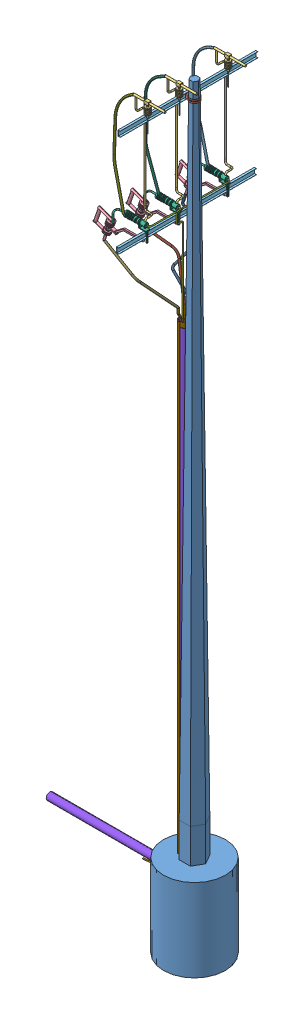
SolidWorks assembly SITEMA DE CABLEADO PARA BAJADA, configuration Predeterminado. Lengths in mm.
Overall size (2551.81 11000 2000).
25 component instances, 17 part files, 70 mates.
Components (placement in the parent):
- POSTE DE SUBESTACIÓN-1: POSTE DE SUBESTACIÓN [Predeterminado] at (-6270.6938 -6573.1724 11000) size (900 11000 900)
- FLEXX-1: FLEXX [Predeterminado] at (-6270.6938 4161.8552 11000) x (-1 0 0) z (0 0 -1) size (154.11 50 136.21)
- CONECTADOR SUPERIOR-1: CONECTADOR SUPERIOR [Predeterminado] at (-6365.6938 4181.216 10415) x (0 0 1) z (-1 0 0) size (176.67 1669.06 455)
- CORTO CIRCUITO FUSIBLE-1: CORTO CIRCUITO FUSIBLE [Predeterminado] at (-6907.9992 2496.6628 11635.8855) x (0 0 -1) z (0.943722 -0.330738 0) size (100 458.14 653.95)
- CORTO CIRCUITO FUSIBLE-2: CORTO CIRCUITO FUSIBLE [Predeterminado] at (-6892.3975 2496.6628 10460.112) x (0 0 -1) z (0.943722 -0.330738 0) size (100 458.14 653.95)
- CORTO CIRCUITO FUSIBLE-3: CORTO CIRCUITO FUSIBLE [Predeterminado] at (-6892.3975 2496.6628 11170.112) x (0 0 -1) z (0.943722 -0.330738 0) size (100 458.14 653.95)
- CRUCETA-1: CRUCETA [Predeterminado] at (-6380.6938 4146.8276 9250) size (54 80 2000)
- CRUCETA-2: CRUCETA [Predeterminado] at (-6400.6938 2666.8276 9250) size (54 80 2000)
- ELEMENTO ELEC.-1: ELEMENTO ELEC. [Predeterminado] at (-6688.5888 2810.6406 11576.0986) x (0 0 1) z (0 1 0) size (120.76 447.39 257.81)
- ELEMENTO ELEC.-2: ELEMENTO ELEC. [Predeterminado] at (-6688.5888 2810.6406 11116.0986) x (0 0 1) z (0 1 0) size (120.76 447.39 257.81)
- ELEMENTO ELEC.-3: ELEMENTO ELEC. [Predeterminado] at (-6688.5888 2810.6406 10406.0986) x (0 0 1) z (0 1 0) size (120.76 447.39 257.81)
- Pieza1^SITEMA DE CABLEADO PARA BAJADA-1: Pieza1^SITEMA DE CABLEADO PARA BAJADA [Predeterminado] at (-6698.5888 2810.6406 10406.0986) x (0 0 -1) z (-1 0 0) (virtual)
- Conexión para rayos-1: Conexión para rayos [Predeterminado] at (-6388.5888 2810.6406 11576.0986) x (0 -0.002991 -0.999996) z (1 0 0) size (1185 605.78 77.17)
- CONECTADOR SUPERIOR-4: CONECTADOR SUPERIOR [Predeterminado] at (-6365.6938 4181.216 11125) x (0 0 1) z (-1 0 0) size (176.67 1669.06 455)
- CONECTADOR SUPERIOR-5: CONECTADOR SUPERIOR [Predeterminado] at (-6365.6938 4181.216 11585) x (0 0 1) z (-1 0 0) size (176.67 1669.06 455)
- Ensamblaje Bajada 4in-1: Ensamblaje Bajada 4in [Predeterminado] at (-5478.9855 4273.2276 7314.2555) x (0 0 -1) z (0 -1 0) size (235.29 2014.23 7584.66)
  - Bajada 4in-1: Bajada 4in [Predeterminado] at (-3685.7445 -940.5199 3026.4) x (0 1 0) z (1 0 0) size (2005.8 7306.8 122.44)
  - Manga para 3 fases-1: Manga para 3 fases [Predeterminado] at (-3685.7445 -940.5199 3148.5365) x (0.995258 -0.097274 0) z (0.097274 0.995258 0) size (199.67 7185.8 375.94)
- Pieza4^SITEMA DE CABLEADO PARA BAJADA-1: Pieza4^SITEMA DE CABLEADO PARA BAJADA [Predeterminado] at (-6933.7398 2378.6975 10460.112) x (0 0 1) z (-0.330738 -0.943722 0) size (476.3 775.26 643.22) (virtual)
- Pieza5^SITEMA DE CABLEADO PARA BAJADA-1: Pieza5^SITEMA DE CABLEADO PARA BAJADA [Predeterminado] at (-6419.5055 1524.691 11000) x (-0.097274 0 -0.995258) z (0 1 0) size (201.42 550.24 868.68) (virtual)
- Pieza6^SITEMA DE CABLEADO PARA BAJADA-1: Pieza6^SITEMA DE CABLEADO PARA BAJADA [Predeterminado] at (-6419.5055 1524.691 11000) x (-0.097274 0 -0.995258) z (0 1 0) size (508.8 611.2 872.94) (virtual)
- Pieza7^SITEMA DE CABLEADO PARA BAJADA-1: Pieza7^SITEMA DE CABLEADO PARA BAJADA [Predeterminado] at (-6419.5055 1324.691 11000) x (-0.097274 0 -0.995258) z (0 1 0) size (94.33 136.48 886.63) (virtual)
- Pieza3^SITEMA DE CABLEADO PARA BAJADA-1: Pieza3^SITEMA DE CABLEADO PARA BAJADA [Predeterminado] at (-6395.6938 4181.216 10415) x (0 0 1) z (-1 0 0) size (78.57 1581.62 325.05) (virtual)
- Pieza8^SITEMA DE CABLEADO PARA BAJADA-1: Pieza8^SITEMA DE CABLEADO PARA BAJADA [Predeterminado] at (-6565.6938 4181.216 11125) x (0 0 1) z (-1 0 0) size (29.07 1561.95 311.16) (virtual)
- Pieza9^SITEMA DE CABLEADO PARA BAJADA-1: Pieza9^SITEMA DE CABLEADO PARA BAJADA [Predeterminado] at (-6565.6938 4181.216 11585) x (0 0 1) z (-1 0 0) size (55.93 1568.55 310.09) (virtual)
Mates (geometry in assembly coordinates):
- Distancia1: distance = 200 mm aligned: plane of POSTE DE SUBESTACIÓN-1 through (-6270.6938 4426.8276 11000) normal (0 1 0); plane of CRUCETA-1 through (-6380.6938 4226.8276 12750) normal (0 1 0)
- Distancia3: distance = 1400 mm anti-aligned: plane of CRUCETA-1 through (-6380.6938 4146.8276 12750) normal (0 -1 0); plane of CRUCETA-2 through (-6400.6938 2746.8276 12750) normal (0 1 0)
- Distancia4: distance = 80 mm aligned: plane of POSTE DE SUBESTACIÓN-1 through (-6270.6938 -6573.1724 11000) normal (1 0 0); plane of CRUCETA-1 through (-6350.6938 4223.8276 12750) normal (1 0 0)
- Distancia5: distance = 100 mm aligned: plane of POSTE DE SUBESTACIÓN-1 through (-6270.6938 -6573.1724 11000) normal (1 0 0); plane of CRUCETA-2 through (-6370.6938 2743.8276 12750) normal (1 0 0)
- Coincidente7: coincident anti-aligned: plane of CONECTADOR SUPERIOR-1 through (-6365.6938 4226.8276 10433.3493) normal (0 -1 0); plane of CRUCETA-1 through (-6380.6938 4226.8276 12750) normal (0 1 0)
- Ancho1: width aligned: plane of CRUCETA-1 through (-6350.6938 4223.8276 12750) normal (1 0 0); plane of CRUCETA-1 through (-6380.6938 4146.8276 12750) normal (-1 0 0); plane of CONECTADOR SUPERIOR-1 through (-6335.6938 4181.216 10415) normal (1 0 0); plane of CONECTADOR SUPERIOR-1 through (-6395.6938 4181.216 10415) normal (-1 0 0)
- Coincidente13: coincident: plane of POSTE DE SUBESTACIÓN-1 through (-6270.6938 -6573.1724 11000) normal (0 0 1); axis of FLEXX-1 through (-6270.6938 4211.7999 11000) axis (0 -1 0)
- Ancho2: width aligned: plane of FLEXX-1 through (-6356.6938 4211.7999 10953.8801) normal (0 1 0); plane of FLEXX-1 through (-6270.6938 4161.8552 11000) normal (0 -1 0); plane of CRUCETA-1 through (-6380.6938 4226.8276 12750) normal (0 1 0); plane of CRUCETA-1 through (-6380.6938 4146.8276 12750) normal (0 -1 0)
- Distancia8: distance = 40 mm anti-aligned: plane of FLEXX-1 through (-6310.6938 4161.8552 11000) normal (-1 0 0); plane of CRUCETA-1 through (-6350.6938 4223.8276 12750) normal (1 0 0)
- Coincidente15: coincident anti-aligned: plane of CRUCETA-2 through (-6400.6938 2746.8276 12750) normal (0 1 0); plane of ELEMENTO ELEC.-3 through (-6370.6938 2746.8276 10436.0986) normal (0 -1 0)
- Coincidente16: coincident aligned: plane of CRUCETA-2 through (-6370.6938 2669.8276 12750) normal (1 0 0); plane of ELEMENTO ELEC.-3 through (-6370.6938 2810.6406 10406.0986) normal (1 0 0)
- Coincidente17: coincident anti-aligned: plane of CRUCETA-2 through (-6400.6938 2746.8276 12750) normal (0 1 0); plane of ELEMENTO ELEC.-2 through (-6370.6938 2746.8276 11146.0986) normal (0 -1 0)
- Coincidente18: coincident aligned: plane of ELEMENTO ELEC.-2 through (-6370.6938 2810.6406 11116.0986) normal (1 0 0); plane of ELEMENTO ELEC.-3 through (-6370.6938 2810.6406 10406.0986) normal (1 0 0)
- Coincidente19: coincident aligned: plane of ELEMENTO ELEC.-1 through (-6370.6938 2810.6406 11576.0986) normal (1 0 0); plane of ELEMENTO ELEC.-2 through (-6370.6938 2810.6406 11116.0986) normal (1 0 0)
- Coincidente20: coincident anti-aligned: plane of CRUCETA-2 through (-6400.6938 2746.8276 12750) normal (0 1 0); plane of ELEMENTO ELEC.-1 through (-6370.6938 2746.8276 11606.0986) normal (0 -1 0)
- Coincidente21: coincident anti-aligned: plane of CORTO CIRCUITO FUSIBLE-2 through (-6653.1137 2666.8276 10449.6736) normal (0 1 0); plane of CRUCETA-2 through (-6400.6938 2666.8276 12750) normal (0 -1 0)
- Coincidente23: coincident anti-aligned: plane of CORTO CIRCUITO FUSIBLE-1 through (-6668.7154 2666.8276 11625.4471) normal (0 1 0); plane of CRUCETA-2 through (-6400.6938 2666.8276 12750) normal (0 -1 0)
- Distancia9: distance = 30 mm anti-aligned: plane of CORTO CIRCUITO FUSIBLE-1 through (-6752.8633 2561.3823 11616.6736) normal (0 0 -1); plane of ELEMENTO ELEC.-1 through (-6386.9618 2592.8276 11586.6736) normal (0 0 1)
- Distancia10: distance = 1000 mm anti-aligned: plane of CRUCETA-1 through (-6380.6938 4146.8276 10000) normal (0 0 -1); plane of POSTE DE SUBESTACIÓN-1 through (-6270.6938 -6573.1724 11000) normal (0 0 1)
- Coincidente25: coincident aligned: plane of CRUCETA-1 through (-6380.6938 4146.8276 10000) normal (0 0 -1); plane of CRUCETA-2 through (-6400.6938 2666.8276 10000) normal (0 0 -1)
- Coincidente28: coincident: line of CORTO CIRCUITO FUSIBLE-1 through (-6370.6938 2643.0396 11646.3239) axis (0 0 -1); plane of CRUCETA-2 through (-6370.6938 2669.8276 12750) normal (1 0 0)
- Coincidente29: coincident anti-aligned: plane of CORTO CIRCUITO FUSIBLE-3 through (-6653.1137 2666.8276 11159.6736) normal (0 1 0); plane of CRUCETA-2 through (-6400.6938 2666.8276 12750) normal (0 -1 0)
- Coincidente30: coincident: line of CORTO CIRCUITO FUSIBLE-3 through (-6370.6938 2666.8276 11159.6736) axis (0 0 1); plane of CRUCETA-2 through (-6370.6938 2669.8276 12750) normal (1 0 0)
- Distancia11: distance = 30 mm anti-aligned: plane of ELEMENTO ELEC.-2 through (-6386.9618 2592.8276 11126.6736) normal (0 0 1); plane of CORTO CIRCUITO FUSIBLE-3 through (-6651.4684 2664.319 11156.6736) normal (0 0 -1)
- Distancia12: distance = 30 mm anti-aligned: plane of ELEMENTO ELEC.-3 through (-6386.9618 2592.8276 10416.6736) normal (0 0 1); plane of CORTO CIRCUITO FUSIBLE-2 through (-6765.7166 2571.3547 10446.6736) normal (0 0 -1)
- Coincidente33: coincident aligned: plane of CONECTADOR SUPERIOR-1 through (-6335.6938 4395.4494 10436.0986) normal (0 0 1); plane of ELEMENTO ELEC.-3 through (-6370.6938 2756.2987 10436.0986) normal (0 0 1)
- Coincidente35: coincident: line of CORTO CIRCUITO FUSIBLE-2 through (-6370.6938 2666.8276 10449.6736) axis (0 0 1); plane of CRUCETA-2 through (-6370.6938 2669.8276 12750) normal (1 0 0)
- EnPosición1: in place: plane of ELEMENTO ELEC.-3 through (-6698.5888 2810.6406 10406.0986) normal (-1 0 0); plane of ? through (-6698.5888 0 0) normal (-1 0 0); moOrthogonalPlaneRef_w of ELEMENTO ELEC.-3 through (-6698.5888 2810.6406 10406.0986) normal (-1 0 0); line of ? through (-55 -6698.5888 0) axis (0 0 1); plane of ELEMENTO ELEC.-3 through (-6698.5888 2810.6406 10406.0986) normal (-1 0 0); plane of ? through (-6698.5888 0 0) normal (0 0 1); plane of ELEMENTO ELEC.-3 through (-6698.5888 2810.6406 10406.0986) normal (-1 0 0); unknown of Pieza1^SITEMA DE CABLEADO PARA BAJADA-1
- Coincidente36: coincident aligned: plane of ELEMENTO ELEC.-3; plane of Pieza1^SITEMA DE CABLEADO PARA BAJADA-1
- Coincidente37: coincident aligned: moOrthogonalPlaneRef_w of ELEMENTO ELEC.-3 through (-6698.5888 2810.6406 10406.0986) normal (0 -1 0); plane of Pieza1^SITEMA DE CABLEADO PARA BAJADA-1
- Coincidente38: coincident anti-aligned: moOrthogonalPlaneRef_w of ELEMENTO ELEC.-3 through (-6698.5888 2810.6406 10406.0986) normal (0 0 1); plane of Pieza1^SITEMA DE CABLEADO PARA BAJADA-1
- Concéntrica1: concentric anti-aligned: cylinder of ELEMENTO ELEC.-1 through (-6688.5888 2810.6406 11576.0986) axis (-1 0 0) radius 30; cylinder of Conexión para rayos-1 through (-6388.5888 2810.6406 11576.0986) axis (1 0 0) radius 7.5
- Coincidente42: coincident anti-aligned: plane of ELEMENTO ELEC.-1 through (-6388.5888 2810.6406 11576.0986) normal (1 0 0); plane of Conexión para rayos-1 through (-6388.5888 2810.6406 11576.0986) normal (-1 0 0)
- Coincidente43: coincident anti-aligned: plane of CRUCETA-1 through (-6380.6938 4226.8276 12750) normal (0 1 0); plane of CONECTADOR SUPERIOR-4 through (-6365.6938 4226.8276 11143.3493) normal (0 -1 0)
- Coincidente44: coincident anti-aligned: plane of CRUCETA-1 through (-6380.6938 4226.8276 12750) normal (0 1 0); plane of CONECTADOR SUPERIOR-5 through (-6365.6938 4226.8276 11603.3493) normal (0 -1 0)
- Coincidente45: coincident aligned: plane of CONECTADOR SUPERIOR-1 through (-6395.6938 4181.216 10415) normal (-1 0 0); plane of CONECTADOR SUPERIOR-4 through (-6395.6938 4181.216 11125) normal (-1 0 0)
- Coincidente46: coincident aligned: plane of CONECTADOR SUPERIOR-4 through (-6395.6938 4181.216 11125) normal (-1 0 0); plane of CONECTADOR SUPERIOR-5 through (-6395.6938 4181.216 11585) normal (-1 0 0)
- Distancia13: distance = 450 mm: cylinder of CONECTADOR SUPERIOR-5 through (-6365.6938 3981.216 11585) axis (0 1 0) radius 5; cylinder of CONECTADOR SUPERIOR-4 through (-6365.6938 3981.216 11125) axis (0 1 0) radius 5
- Distancia14: distance = 700 mm: cylinder of CONECTADOR SUPERIOR-1 through (-6365.6938 3981.216 10415) axis (0 1 0) radius 5; cylinder of CONECTADOR SUPERIOR-4 through (-6365.6938 3981.216 11125) axis (0 1 0) radius 5
- Ancho4: width aligned: plane of CRUCETA-1 through (-6380.6938 4146.8276 12000) normal (0 0 1); plane of CRUCETA-1 through (-6380.6938 4146.8276 10000) normal (0 0 -1); plane of CONECTADOR SUPERIOR-5 through (-6335.6938 4395.4494 11606.0986) normal (0 0 1); plane of CONECTADOR SUPERIOR-1 through (-6335.6938 4395.4494 10393.9014) normal (0 0 -1)
- Coincidente47: coincident aligned: plane of ELEMENTO ELEC.-1 through (-6370.6938 2756.2987 11606.0986) normal (0 0 1); plane of CONECTADOR SUPERIOR-5 through (-6335.6938 4395.4494 11606.0986) normal (0 0 1)
- Coincidente48: coincident aligned: plane of ELEMENTO ELEC.-2 through (-6370.6938 2756.2987 11146.0986) normal (0 0 1); plane of CONECTADOR SUPERIOR-4 through (-6335.6938 4395.4494 11146.0986) normal (0 0 1)
- EnPosición3: in place: plane of CORTO CIRCUITO FUSIBLE-2 through (-6933.7398 2378.6975 10460.112) normal (-0.330738 -0.943722 0); plane of ? through (-16.0155 -45.6982 0) normal (-0.330738 -0.943722 0); plane of CORTO CIRCUITO FUSIBLE-2 through (-6933.7398 2378.6975 10460.112) normal (-0.330738 -0.943722 0); unknown of ?; plane of CORTO CIRCUITO FUSIBLE-2 through (-6933.7398 2378.6975 10460.112) normal (-0.330738 -0.943722 0); unknown of ?; plane of CORTO CIRCUITO FUSIBLE-2 through (-6933.7398 2378.6975 10460.112) normal (-0.330738 -0.943722 0); unknown of Pieza4^SITEMA DE CABLEADO PARA BAJADA-1
- Coincidente55: coincident aligned: plane of CORTO CIRCUITO FUSIBLE-2; plane of Pieza4^SITEMA DE CABLEADO PARA BAJADA-1
- Coincidente56: coincident aligned: moOrthogonalPlaneRef_w of CORTO CIRCUITO FUSIBLE-2 through (-6933.7398 2378.6975 10460.112) normal (-0.943722 0.330738 0); plane of Pieza4^SITEMA DE CABLEADO PARA BAJADA-1
- Coincidente57: coincident anti-aligned: moOrthogonalPlaneRef_w of CORTO CIRCUITO FUSIBLE-2 through (-6933.7398 2378.6975 10460.112) normal (0 0 -1); plane of Pieza4^SITEMA DE CABLEADO PARA BAJADA-1
- EnPosición4: in place: plane of Ensamblaje Bajada 4in-1/Manga para 3 fases-1 through (-6419.5055 1524.691 11000) normal (0 1 0); plane of ? through (0 1524.691 0) normal (0 1 0); plane of Ensamblaje Bajada 4in-1/Manga para 3 fases-1 through (-6419.5055 1524.691 11000) normal (0 1 0); plane of ? through (0 1524.691 0) normal (0 0 -1); plane of Ensamblaje Bajada 4in-1/Manga para 3 fases-1 through (-6419.5055 1524.691 11000) normal (0 1 0); unknown of ?; plane of Ensamblaje Bajada 4in-1/Manga para 3 fases-1 through (-6419.5055 1524.691 11000) normal (0 1 0); unknown of ?
- Coincidente58: coincident aligned: plane of Ensamblaje Bajada 4in-1/Manga para 3 fases-1; plane of Pieza5^SITEMA DE CABLEADO PARA BAJADA-1
- Coincidente59: coincident aligned: moOrthogonalPlaneRef_w of Ensamblaje Bajada 4in-1/Manga para 3 fases-1 through (-6419.5055 1524.691 11000) normal (-0.995258 0 0.097274); plane of Pieza5^SITEMA DE CABLEADO PARA BAJADA-1
- Coincidente60: coincident anti-aligned: moOrthogonalPlaneRef_w of Ensamblaje Bajada 4in-1/Manga para 3 fases-1 through (-6419.5055 1524.691 11000) normal (0.097274 0 0.995258); plane of Pieza5^SITEMA DE CABLEADO PARA BAJADA-1
- EnPosición5: in place: plane of Ensamblaje Bajada 4in-1/Manga para 3 fases-1 through (-6419.5055 1524.691 11000) normal (0 1 0); plane of ? through (0 1524.691 0) normal (0 1 0); plane of Ensamblaje Bajada 4in-1/Manga para 3 fases-1 through (-6419.5055 1524.691 11000) normal (0 1 0); plane of ? through (0 1524.691 0) normal (0 0 -1); plane of Ensamblaje Bajada 4in-1/Manga para 3 fases-1 through (-6419.5055 1524.691 11000) normal (0 1 0); unknown of ?; plane of Ensamblaje Bajada 4in-1/Manga para 3 fases-1 through (-6419.5055 1524.691 11000) normal (0 1 0); unknown of ?
- Coincidente61: coincident aligned: plane of Ensamblaje Bajada 4in-1/Manga para 3 fases-1; plane of Pieza6^SITEMA DE CABLEADO PARA BAJADA-1
- Coincidente62: coincident aligned: moOrthogonalPlaneRef_w of Ensamblaje Bajada 4in-1/Manga para 3 fases-1 through (-6419.5055 1524.691 11000) normal (-0.995258 0 0.097274); plane of Pieza6^SITEMA DE CABLEADO PARA BAJADA-1
- Coincidente63: coincident anti-aligned: moOrthogonalPlaneRef_w of Ensamblaje Bajada 4in-1/Manga para 3 fases-1 through (-6419.5055 1524.691 11000) normal (0.097274 0 0.995258); plane of Pieza6^SITEMA DE CABLEADO PARA BAJADA-1
- EnPosición6: in place: plane of Ensamblaje Bajada 4in-1/Manga para 3 fases-1 through (-6438.8656 1324.691 11060.3178) normal (0 1 0); plane of ? through (0 1324.691 0) normal (0 1 0); plane of Ensamblaje Bajada 4in-1/Manga para 3 fases-1 through (-6438.8656 1324.691 11060.3178) normal (0 1 0); plane of ? through (0 1324.691 0) normal (0 0 -1); plane of Ensamblaje Bajada 4in-1/Manga para 3 fases-1 through (-6438.8656 1324.691 11060.3178) normal (0 1 0); unknown of ?; plane of Ensamblaje Bajada 4in-1/Manga para 3 fases-1 through (-6438.8656 1324.691 11060.3178) normal (0 1 0); unknown of Pieza7^SITEMA DE CABLEADO PARA BAJADA-1
- Coincidente64: coincident aligned: plane of Ensamblaje Bajada 4in-1/Manga para 3 fases-1; plane of Pieza7^SITEMA DE CABLEADO PARA BAJADA-1
- Coincidente65: coincident aligned: moOrthogonalPlaneRef_w of Ensamblaje Bajada 4in-1/Manga para 3 fases-1 through (-6419.5055 1324.691 11000) normal (-0.995258 0 0.097274); plane of Pieza7^SITEMA DE CABLEADO PARA BAJADA-1
- Coincidente66: coincident anti-aligned: moOrthogonalPlaneRef_w of Ensamblaje Bajada 4in-1/Manga para 3 fases-1 through (-6419.5055 1324.691 11000) normal (0.097274 0 0.995258); plane of Pieza7^SITEMA DE CABLEADO PARA BAJADA-1
- EnPosición8: in place: plane of CONECTADOR SUPERIOR-1 through (-6395.6938 4181.216 10415) normal (-1 0 0); plane of ? through (-6395.6938 0 0) normal (-1 0 0); plane of CONECTADOR SUPERIOR-1 through (-6395.6938 4181.216 10415) normal (-1 0 0); line of ? through (-55 -6395.6938 0) axis (0 0 1); plane of CONECTADOR SUPERIOR-1 through (-6395.6938 4181.216 10415) normal (-1 0 0); plane of ? through (-6395.6938 0 0) normal (0 0 1); plane of CONECTADOR SUPERIOR-1 through (-6395.6938 4181.216 10415) normal (-1 0 0); unknown of Pieza3^SITEMA DE CABLEADO PARA BAJADA-1
- Coincidente52: coincident aligned: plane of CONECTADOR SUPERIOR-1; plane of Pieza3^SITEMA DE CABLEADO PARA BAJADA-1
- Coincidente53: coincident aligned: moOrthogonalPlaneRef_w of CONECTADOR SUPERIOR-1 through (-6395.6938 4181.216 10415) normal (0 1 0); plane of Pieza3^SITEMA DE CABLEADO PARA BAJADA-1
- Coincidente54: coincident anti-aligned: moOrthogonalPlaneRef_w of CONECTADOR SUPERIOR-1 through (-6395.6938 4181.216 10415) normal (0 0 -1); plane of Pieza3^SITEMA DE CABLEADO PARA BAJADA-1 through (-6395.6938 4181.216 10415) normal (0 0 1)
- EnPosición9: in place: plane of CONECTADOR SUPERIOR-4 through (-6565.6938 4374.7377 11125) normal (-1 0 0); plane of ? through (-6565.6938 0 0) normal (-1 0 0); plane of CONECTADOR SUPERIOR-4 through (-6565.6938 4374.7377 11125) normal (-1 0 0); line of ? through (-55 -6565.6938 0) axis (0 0 1); plane of CONECTADOR SUPERIOR-4 through (-6565.6938 4374.7377 11125) normal (-1 0 0); plane of ? through (-6565.6938 0 0) normal (0 0 1); plane of CONECTADOR SUPERIOR-4 through (-6565.6938 4374.7377 11125) normal (-1 0 0); unknown of Pieza8^SITEMA DE CABLEADO PARA BAJADA-1
- Coincidente55: coincident aligned: plane of CONECTADOR SUPERIOR-4; plane of Pieza8^SITEMA DE CABLEADO PARA BAJADA-1
- Coincidente56: coincident aligned: moOrthogonalPlaneRef_w of CONECTADOR SUPERIOR-4 through (-6565.6938 4181.216 11125) normal (0 1 0); plane of Pieza8^SITEMA DE CABLEADO PARA BAJADA-1
- Coincidente57: coincident anti-aligned: moOrthogonalPlaneRef_w of CONECTADOR SUPERIOR-4 through (-6565.6938 4181.216 11125) normal (0 0 -1); plane of Pieza8^SITEMA DE CABLEADO PARA BAJADA-1 through (-6565.6938 4181.216 11125) normal (0 0 1)
- EnPosición10: in place: plane of CONECTADOR SUPERIOR-5 through (-6565.6938 4374.7377 11585) normal (-1 0 0); plane of ? through (-6565.6938 0 0) normal (-1 0 0); plane of CONECTADOR SUPERIOR-5 through (-6565.6938 4374.7377 11585) normal (-1 0 0); line of ? through (-55 -6565.6938 0) axis (0 0 1); plane of CONECTADOR SUPERIOR-5 through (-6565.6938 4374.7377 11585) normal (-1 0 0); plane of ? through (-6565.6938 0 0) normal (0 0 1); plane of CONECTADOR SUPERIOR-5 through (-6565.6938 4374.7377 11585) normal (-1 0 0); unknown of Pieza9^SITEMA DE CABLEADO PARA BAJADA-1
- Coincidente58: coincident aligned: plane of CONECTADOR SUPERIOR-5; plane of Pieza9^SITEMA DE CABLEADO PARA BAJADA-1
- Coincidente59: coincident aligned: moOrthogonalPlaneRef_w of CONECTADOR SUPERIOR-5 through (-6565.6938 4181.216 11585) normal (0 1 0); plane of Pieza9^SITEMA DE CABLEADO PARA BAJADA-1
- Coincidente60: coincident anti-aligned: moOrthogonalPlaneRef_w of CONECTADOR SUPERIOR-5 through (-6565.6938 4181.216 11585) normal (0 0 -1); plane of Pieza9^SITEMA DE CABLEADO PARA BAJADA-1 through (-6565.6938 4181.216 11585) normal (0 0 1)
